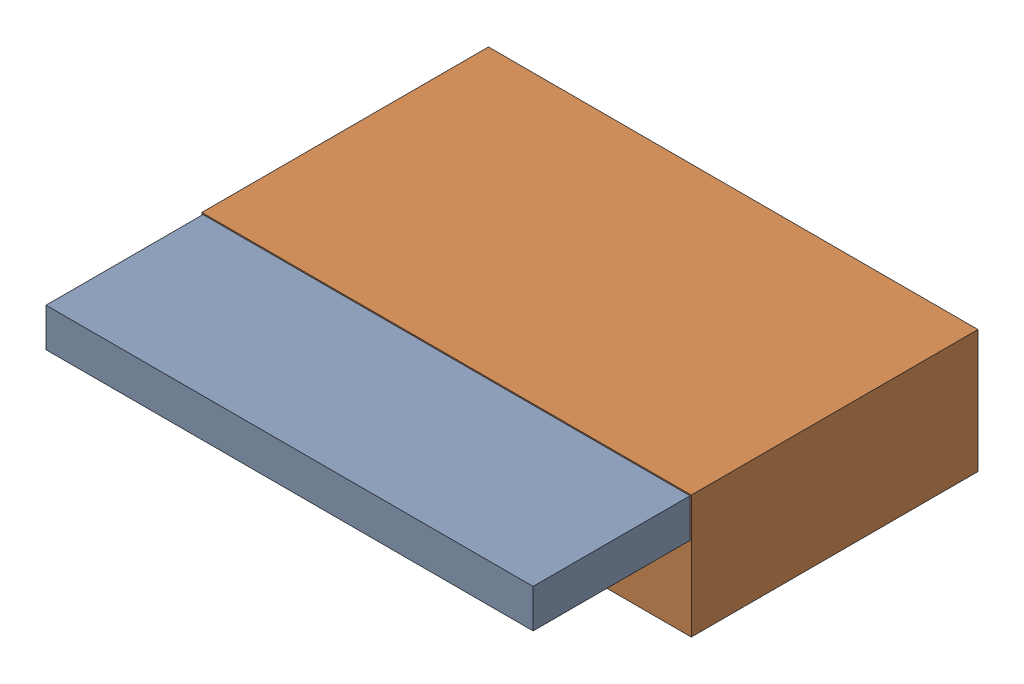
SolidWorks assembly U2, configuration Default. Lengths in mm.
Overall size (20.3 5.1 18.4).
4 component instances, 2 part files, 0 mates.
Components (placement in the parent):
- -1733505456-1: -1733505456 [Default] at (471.92 301.75 14.49) size (20.2 1.6 6.51)
  - Extruded-1: Extruded [Default] at origin size (20.2 1.6 6.51)
- -1733503536-1: -1733503536 [Default] at (471.92 300.05 2.6) size (20.3 5.1 11.89)
  - Extruded_2-1: Extruded_2 [Default] at origin size (20.3 5.1 11.89)
